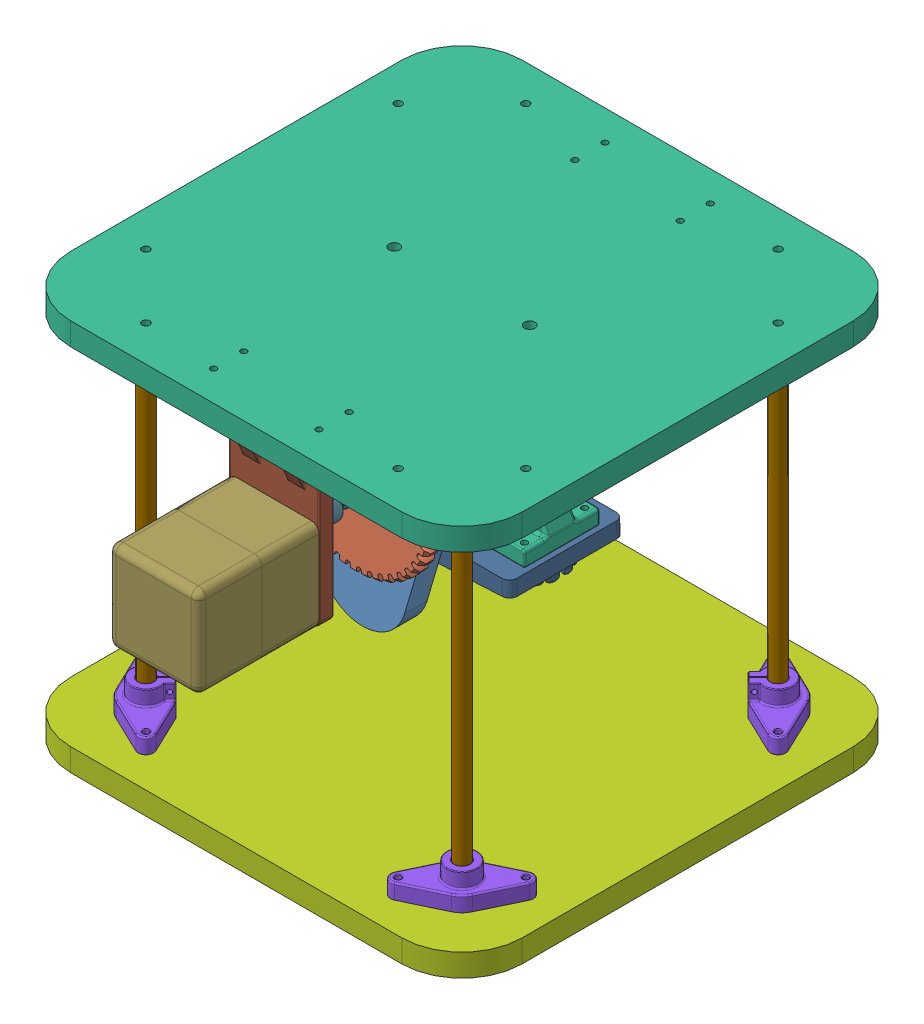
SolidWorks assembly ASSEMBLY Full Design 7th Attempt - New Design For Jaw, configuration Default. Lengths in mm.
Overall size (300 260 410).
35 component instances, 15 part files, 88 mates.
Components (placement in the parent):
- Main Case 02-1: Main Case 02 [Default] x (0.994892 -0.100948 0) z (0 0 1) size (80 129 15)
- Secondary Big Spur Gear-1: Secondary Big Spur Gear [Default] at (0 0 66) x (0.839597 -0.54321 0) z (0 0 1) size (100.6 100.6 10)
- Main Bearing-1: Main Bearing [Default] at (0 0 52.5) x (0.766521 -0.642219 0) z (0 0 1) size (25 25 10)
- Secondary Big Spur Gear-2: Secondary Big Spur Gear [Default] at (0 0 -66) x (-0.772467 -0.635055 0) z (0 0 1) size (100.6 100.6 10)
- Main Bearing-3: Main Bearing [Default] at (0 0 -55) x (0.693553 -0.720406 0) z (0 0 1) size (25 25 10)
- Main Rod-1: Main Rod [Default] at origin size (10 10 70)
- Rod Cap-1: Rod Cap [Default] at (0 0 -35) x (-0.994892 0.100948 0) z (0 0 1) size (44.95 22.5 20)
- Rod Cap-2: Rod Cap [Default] at (0 0 35) x (-0.994892 0.100948 0) z (0 0 1) size (44.95 22.5 20)
- Top Bracket-1: Top Bracket [Default] at (0 72.5 0) size (300 116.9 300)
- Main Bearing-5: Main Bearing [Default] at (0 0 18) size (25 25 10)
- Main Bearing-6: Main Bearing [Default] at (0 0 -18) size (25 25 10)
- Bottom Bracket-1: Bottom Bracket [Default] at (0 -180 0) size (300 15 300)
- Plate Docker-1: Plate Docker [Default] at (105 -165 -105) x (0.707107 0 0.707107) z (-0.707107 0 0.707107) size (70 20.03 29.14)
- Plate Docker-2: Plate Docker [Default] at (105 65 105) x (0.707107 0 -0.707107) z (-0.707107 0 -0.707107) size (70 20.03 29.14)
- Plate Docker-3: Plate Docker [Default] at (-105 65 -105) x (-0.707107 0 0.707107) z (0.707107 0 0.707107) size (70 20.03 29.14)
- Plate Docker-4: Plate Docker [Default] at (-105 -165 105) x (-0.707107 0 -0.707107) z (0.707107 0 -0.707107) size (70 20.03 29.14)
- Plate Docker-5: Plate Docker [Default] at (-105 -165 -105) x (0.707107 0 -0.707107) z (0.707107 0 0.707107) size (70 20.03 29.14)
- Plate Docker-6: Plate Docker [Default] at (-105 65 105) x (0.707107 0 0.707107) z (0.707107 0 -0.707107) size (70 20.03 29.14)
- Plate Docker-7: Plate Docker [Default] at (105 65 -105) x (-0.707107 0 -0.707107) z (-0.707107 0 0.707107) size (70 20.03 29.14)
- Plate Docker-8: Plate Docker [Default] at (105 -165 105) x (-0.707107 0 0.707107) z (-0.707107 0 -0.707107) size (70 20.03 29.14)
- Bracket Shaft-1: Bracket Shaft [Default] at (-105 -165 105) size (10 230 10)
- Bracket Shaft-2: Bracket Shaft [Default] at (-105 -165 -105) size (10 230 10)
- Bracket Shaft-3: Bracket Shaft [Default] at (105 -165 105) size (10 230 10)
- Bracket Shaft-4: Bracket Shaft [Default] at (105 -165 -105) size (10 230 10)
- Ham tren V1-2: Ham tren V1 [Default] at (38.2293 -54.5924 0.5024) x (0 0 -1) z (-0.121869 -0.992546 0) size (76.11 57.29 25.91)
- Motor Mount Plate-1: Motor Mount Plate [Default] at (0 12.5 115) size (80 105 30)
- Motor Mount Plate-2: Motor Mount Plate [Default] at (0 12.5 -125) size (80 105 30)
- Motor-1: Motor [Default] at (-30.0013 -39.9987 163) size (60 60 99)
- Motor-2: Motor [Default] at (30.0013 -39.9987 -163) x (-1 0 0) z (0 0 -1) size (60 60 99)
- Big Motor Shaft-1: Big Motor Shaft [Default] at (0 0 -100) x (0.73445 0.678663 0) z (0.678663 -0.73445 0) size (10 50 10)
- Big Motor Shaft-2: Big Motor Shaft [Default] at (0 0 50) x (0.969145 0.246493 0) z (0.246493 -0.969145 0) size (10 50 10)
- Motor Coupling-1: Motor Coupling [Default] at (0.0013 0.0013 -100.5) x (-1 0 0) z (0 0 -1) size (20 20 25)
- Motor Coupling-2: Motor Coupling [Default] at (-0.0013 0.0013 100.5) size (20 20 25)
- Shaft Lock-3: Shaft Lock [Default] at (0 0 71) x (1 0 0) z (0 -1 0) size (20 10 20)
- Shaft Lock-4: Shaft Lock [Default] at (0 0 -71) x (-1 0 0) z (0 -1 0) size (20 10 20)
Mates (geometry in assembly coordinates):
- Coincident1: coincident aligned: plane of Main Case 02-1 through (0 0 0) normal (0 0 1)
- Concentric2: concentric aligned: cylinder of Main Case 02-1 through (0 0 45) axis (0 0 1) radius 12.5; cylinder of Secondary Big Spur Gear-1 through (0 0 61) axis (0 0 1) radius 5
- Distance1: distance = 1 mm anti-aligned: plane of Secondary Big Spur Gear-1 through (0 0 61) normal (0 0 -1); plane of Main Case 02-1 through (0 0 60) normal (0 0 1)
- Concentric3: concentric anti-aligned: cylinder of Main Case 02-1 through (0 0 45) axis (0 0 1) radius 12.5; cylinder of Main Bearing-1 through (0 0 57.5) axis (0 0 -1) radius 12.5
- Width1: width aligned: plane of Main Bearing-1 through (0 0 47.5) normal (0 0 -1); plane of Main Bearing-1 through (0 0 57.5) normal (0 0 1); plane of Main Case 02-1 through (0 0 45) normal (0 0 -1); plane of Main Case 02-1 through (0 0 60) normal (0 0 1)
- Concentric11: concentric: cylinder of Main Case 02-1 through (0 0 -45) axis (0 0 -1) radius 12.5; cylinder of Secondary Big Spur Gear-2 through (0 0 -71) axis (0 0 1) radius 5
- Distance4: distance = 1 mm: plane of Secondary Big Spur Gear-2 through (0 0 -61) normal (0 0 1); plane of Main Case 02-1 through (0 0 -60) normal (0 0 -1)
- Concentric15: concentric: cylinder of Main Case 02-1 through (0 0 -45) axis (0 0 -1) radius 12.5; cylinder of Main Bearing-3 through (0 0 -50) axis (0 0 -1) radius 5
- Coincident19: coincident: point of Main Case 02-1; point of assembly
- Coincident20: coincident: plane of Main Case 02-1 through (0 0 -60) normal (0 0 -1); plane of Main Bearing-3 through (0 0 -60) normal (0 0 -1)
- Concentric20: concentric: cylinder of Main Case 02-1 through (0 0 35) axis (0 0 -1) radius 5; cylinder of Main Rod-1 through (0 0 35) axis (0 0 -1) radius 5
- Coincident21: coincident: plane of Main Case 02-1 through (0 0 -35) normal (0 0 1); plane of Main Rod-1 through (0 0 -35) normal (0 0 -1)
- Coincident22: coincident: plane of Main Case 02-1 through (-22.3851 2.2713 -25) normal (0.100948 0.994892 0); plane of Rod Cap-1 through (22.3851 -2.2713 -25) normal (-0.100948 -0.994892 0)
- Concentric21: concentric: cylinder of Main Case 02-1 through (11.6608 -21.2859 -35) axis (0.100948 0.994892 0) radius 2; cylinder of Rod Cap-1 through (15.9511 20.997 -35) axis (-0.100948 -0.994892 0) radius 2
- Concentric22: concentric: cylinder of Main Case 02-1 through (-15.6987 -18.5098 -35) axis (0.100948 0.994892 0) radius 2; cylinder of Rod Cap-1 through (-11.4084 23.7731 -35) axis (-0.100948 -0.994892 0) radius 2
- Concentric23: concentric: cylinder of Main Case 02-1 through (11.6608 -21.2859 35) axis (0.100948 0.994892 0) radius 2; cylinder of Rod Cap-2 through (15.9511 20.997 35) axis (-0.100948 -0.994892 0) radius 2
- Coincident23: coincident: plane of Main Case 02-1 through (-22.3851 2.2713 25) normal (0.100948 0.994892 0); plane of Rod Cap-2 through (22.3851 -2.2713 45) normal (-0.100948 -0.994892 0)
- Concentric24: concentric: cylinder of Main Case 02-1 through (-15.6987 -18.5098 35) axis (0.100948 0.994892 0) radius 2; cylinder of Rod Cap-2 through (-11.4084 23.7731 35) axis (-0.100948 -0.994892 0) radius 2
- Concentric26: concentric anti-aligned: cylinder of Main Rod-1 through (0 0 35) axis (0 0 -1) radius 5; cylinder of Top Bracket-1 through (0 0 13) axis (0 0 1) radius 10
- Width4: width: plane of Main Case 02-1 through (0 0 -45) normal (0 0 1); plane of Top Bracket-1 through (0 0 45) normal (0 0 -1); plane of Main Case 02-1 through (0 0 -23) normal (0 0 -1); plane of Top Bracket-1 through (0 0 23) normal (0 0 1)
- Parallel9: parallel anti-aligned: plane of Top Bracket-1 through (-150 65 150) normal (0 -1 0)
- Coincident33: coincident aligned: plane of Top Bracket-1 through (0 0 -23) normal (0 0 -1); plane of Main Bearing-6 through (0 0 -23) normal (0 0 -1)
- Concentric28: concentric aligned: cylinder of Main Rod-1 through (0 0 35) axis (0 0 -1) radius 5; cylinder of Main Bearing-6 through (0 0 -13) axis (0 0 -1) radius 5
- Coincident34: coincident aligned: plane of Top Bracket-1 through (0 0 23) normal (0 0 1); plane of Main Bearing-5 through (0 0 23) normal (0 0 1)
- Concentric29: concentric aligned: cylinder of Main Rod-1 through (0 0 35) axis (0 0 -1) radius 5; cylinder of Main Bearing-5 through (0 0 23) axis (0 0 -1) radius 5
- Coincident35: coincident aligned: plane of Top Bracket-1 through (0 72.5 0) normal (0 0 1); plane of Bottom Bracket-1 through (0 -180 0) normal (0 0 1)
- Coincident36: coincident aligned: plane of Top Bracket-1 through (0 72.5 0) normal (1 0 0); plane of Bottom Bracket-1 through (0 -180 0) normal (1 0 0)
- Distance6: distance = 230 mm anti-aligned: plane of Bottom Bracket-1 through (0 -165 0) normal (0 1 0); plane of Top Bracket-1 through (-150 65 150) normal (0 -1 0)
- Concentric30: concentric anti-aligned: circle of Bottom Bracket-1; cylinder of Plate Docker-1 through (105 -155 -105) axis (0 -1 0) radius 5
- Coincident37: coincident anti-aligned: plane of Bottom Bracket-1 through (0 -165 0) normal (0 1 0); plane of Plate Docker-1 through (83.7868 -165 -126.2132) normal (0 -1 0)
- Concentric31: concentric aligned: cylinder of Bottom Bracket-1 through (126.2132 -180 -83.7868) axis (0 1 0) radius 2.5; cylinder of Plate Docker-1 through (126.2132 -165 -83.7868) axis (0 1 0) radius 2
- Concentric32: concentric aligned: cylinder of Bottom Bracket-1 through (-126.2132 -180 -83.7868) axis (0 1 0) radius 2.5; cylinder of Plate Docker-5 through (-126.2132 -165 -83.7868) axis (0 1 0) radius 2
- Coincident38: coincident anti-aligned: plane of Bottom Bracket-1 through (0 -165 0) normal (0 1 0); plane of Plate Docker-5 through (-126.2132 -165 -83.7868) normal (0 -1 0)
- Concentric33: concentric aligned: cylinder of Bottom Bracket-1 through (-83.7868 -180 -126.2132) axis (0 1 0) radius 2.5; cylinder of Plate Docker-5 through (-83.7868 -165 -126.2132) axis (0 1 0) radius 2
- Coincident39: coincident anti-aligned: plane of Bottom Bracket-1 through (0 -165 0) normal (0 1 0); plane of Plate Docker-8 through (126.2132 -165 83.7868) normal (0 -1 0)
- Concentric35: concentric aligned: cylinder of Bottom Bracket-1 through (83.7868 -180 126.2132) axis (0 1 0) radius 2.5; cylinder of Plate Docker-8 through (83.7868 -165 126.2132) axis (0 1 0) radius 2
- Concentric36: concentric aligned: cylinder of Bottom Bracket-1 through (126.2132 -180 83.7868) axis (0 1 0) radius 2.5; cylinder of Plate Docker-8 through (126.2132 -165 83.7868) axis (0 1 0) radius 2
- Coincident40: coincident anti-aligned: plane of Bottom Bracket-1 through (0 -165 0) normal (0 1 0); plane of Plate Docker-4 through (-83.7868 -165 126.2132) normal (0 -1 0)
- Concentric37: concentric aligned: cylinder of Bottom Bracket-1 through (-126.2132 -180 83.7868) axis (0 1 0) radius 2.5; cylinder of Plate Docker-4 through (-126.2132 -165 83.7868) axis (0 1 0) radius 2
- Concentric38: concentric aligned: cylinder of Bottom Bracket-1 through (-83.7868 -180 126.2132) axis (0 1 0) radius 2.5; cylinder of Plate Docker-4 through (-83.7868 -165 126.2132) axis (0 1 0) radius 2
- Coincident42: coincident anti-aligned: plane of Top Bracket-1 through (-150 65 150) normal (0 -1 0); plane of Plate Docker-2 through (83.7868 65 126.2132) normal (0 1 0)
- Concentric40: concentric aligned: cylinder of Top Bracket-1 through (83.7868 80 126.2132) axis (0 -1 0) radius 2.5; cylinder of Plate Docker-2 through (83.7868 65 126.2132) axis (0 -1 0) radius 2
- Concentric41: concentric aligned: cylinder of Top Bracket-1 through (126.2132 80 83.7868) axis (0 -1 0) radius 2.5; cylinder of Plate Docker-2 through (126.2132 65 83.7868) axis (0 -1 0) radius 2
- Coincident43: coincident anti-aligned: plane of Top Bracket-1 through (-150 65 150) normal (0 -1 0); plane of Plate Docker-6 through (-126.2132 65 83.7868) normal (0 1 0)
- Concentric42: concentric aligned: cylinder of Top Bracket-1 through (-83.7868 80 126.2132) axis (0 -1 0) radius 2.5; cylinder of Plate Docker-6 through (-83.7868 65 126.2132) axis (0 -1 0) radius 2
- Concentric43: concentric aligned: cylinder of Top Bracket-1 through (-126.2132 80 83.7868) axis (0 -1 0) radius 2.5; cylinder of Plate Docker-6 through (-126.2132 65 83.7868) axis (0 -1 0) radius 2
- Coincident44: coincident anti-aligned: plane of Top Bracket-1 through (-150 65 150) normal (0 -1 0); plane of Plate Docker-3 through (-83.7868 65 -126.2132) normal (0 1 0)
- Concentric45: concentric aligned: cylinder of Top Bracket-1 through (-83.7868 80 -126.2132) axis (0 -1 0) radius 2.5; cylinder of Plate Docker-3 through (-83.7868 65 -126.2132) axis (0 -1 0) radius 2
- Concentric46: concentric aligned: cylinder of Top Bracket-1 through (-126.2132 80 -83.7868) axis (0 -1 0) radius 2.5; cylinder of Plate Docker-3 through (-126.2132 65 -83.7868) axis (0 -1 0) radius 2
- Coincident45: coincident anti-aligned: plane of Top Bracket-1 through (-150 65 150) normal (0 -1 0); plane of Plate Docker-7 through (126.2132 65 -83.7868) normal (0 1 0)
- Concentric47: concentric aligned: cylinder of Top Bracket-1 through (83.7868 80 -126.2132) axis (0 -1 0) radius 2.5; cylinder of Plate Docker-7 through (83.7868 65 -126.2132) axis (0 -1 0) radius 2
- Concentric48: concentric aligned: cylinder of Top Bracket-1 through (126.2132 80 -83.7868) axis (0 -1 0) radius 2.5; cylinder of Plate Docker-7 through (126.2132 65 -83.7868) axis (0 -1 0) radius 2
- Concentric49: concentric aligned: cylinder of Plate Docker-4 through (-105 -155 105) axis (0 -1 0) radius 5; cylinder of Bracket Shaft-1 through (-105 65 105) axis (0 -1 0) radius 5
- Coincident46: coincident anti-aligned: plane of Top Bracket-1 through (-150 65 150) normal (0 -1 0); plane of Bracket Shaft-1 through (-105 65 105) normal (0 1 0)
- Concentric50: concentric anti-aligned: cylinder of Plate Docker-7 through (105 55 -105) axis (0 1 0) radius 5; cylinder of Bracket Shaft-4 through (105 65 -105) axis (0 -1 0) radius 5
- Coincident47: coincident anti-aligned: plane of Top Bracket-1 through (-150 65 150) normal (0 -1 0); plane of Bracket Shaft-4 through (105 65 -105) normal (0 1 0)
- Concentric51: concentric anti-aligned: cylinder of Plate Docker-2 through (105 45 105) axis (0 1 0) radius 10; cylinder of Bracket Shaft-3 through (105 65 105) axis (0 -1 0) radius 5
- Coincident48: coincident anti-aligned: plane of Top Bracket-1 through (-150 65 150) normal (0 -1 0); plane of Bracket Shaft-3 through (105 65 105) normal (0 1 0)
- Concentric52: concentric aligned: cylinder of Plate Docker-5 through (-105 -155 -105) axis (0 -1 0) radius 5; cylinder of Bracket Shaft-2 through (-105 65 -105) axis (0 -1 0) radius 5
- Coincident49: coincident anti-aligned: plane of Top Bracket-1 through (-150 65 150) normal (0 -1 0); plane of Bracket Shaft-2 through (-105 65 -105) normal (0 1 0)
- Coincident73: coincident anti-aligned: plane of Top Bracket-1 through (16.5 -36.9 25) normal (0 -1 0); plane of Ham tren V1-2 through (38.2293 -36.9 -94.448) normal (0 1 0)
- Concentric59: concentric aligned: cylinder of Top Bracket-1 through (61.5 -46.9 -20) axis (0 1 0) radius 2; cylinder of Ham tren V1-2 through (61.5 -44.9 -20) axis (0 1 0) radius 2
- Concentric60: concentric aligned: cylinder of Top Bracket-1 through (61.5 -46.9 20) axis (0 1 0) radius 2; cylinder of Ham tren V1-2 through (61.5 -44.9 20) axis (0 1 0) radius 2
- Coincident74: coincident anti-aligned: plane of Top Bracket-1 through (-150 65 150) normal (0 -1 0); plane of Motor Mount Plate-1 through (-30 65 125) normal (0 1 0)
- Coincident75: coincident anti-aligned: plane of Top Bracket-1 through (-150 65 150) normal (0 -1 0); plane of Motor Mount Plate-2 through (-30 65 -115) normal (0 1 0)
- Concentric61: concentric anti-aligned: cylinder of Top Bracket-1 through (-35 80 -130) axis (0 -1 0) radius 2; cylinder of Motor Mount Plate-2 through (-35 55 -130) axis (0 1 0) radius 2
- Concentric62: concentric anti-aligned: cylinder of Top Bracket-1 through (35 80 -110) axis (0 -1 0) radius 2; cylinder of Motor Mount Plate-2 through (35 55 -110) axis (0 1 0) radius 2
- Concentric63: concentric anti-aligned: cylinder of Top Bracket-1 through (35 80 130) axis (0 -1 0) radius 2; cylinder of Motor Mount Plate-1 through (35 55 130) axis (0 1 0) radius 2
- Concentric64: concentric anti-aligned: cylinder of Top Bracket-1 through (-35 80 110) axis (0 -1 0) radius 2; cylinder of Motor Mount Plate-1 through (-35 55 110) axis (0 1 0) radius 2
- Coincident76: coincident anti-aligned: plane of Motor Mount Plate-1 through (0 12.5 125) normal (0 0 1); plane of Motor-1 through (-30.0013 -39.9987 125) normal (0 0 -1)
- Tangent1: tangent aligned: cylinder of Motor-1 through (-24.75 14.75 135) axis (0 0 -1) radius 2.25; cylinder of Motor Mount Plate-1 through (-24.75 14.75 105) axis (0 0 1) radius 2.25
- Coincident78: coincident anti-aligned: plane of Motor Mount Plate-2 through (0 12.5 -125) normal (0 0 -1); plane of Motor-2 through (30.0013 -39.9987 -125) normal (0 0 1)
- Concentric71: concentric aligned: cylinder of Motor Mount Plate-2 through (24.75 14.75 -135) axis (0 0 1) radius 2.25; cylinder of Motor-2 through (24.75 14.75 -135) axis (0 0 1) radius 2.25
- Parallel28: parallel aligned: cylinder of Motor Mount Plate-2 through (-24.75 14.75 -135) axis (0 0 1) radius 2.25; cylinder of Motor-2 through (-24.7475 14.75 -135) axis (0 0 1) radius 2.25
- Parallel29: parallel aligned: plane of Motor Mount Plate-1 through (0 12.5 115) normal (1 0 0); plane of Motor-1 through (-30.0013 -39.9987 163) normal (1 0 0)
- Parallel30: parallel anti-aligned: plane of Motor Mount Plate-2 through (0 12.5 -125) normal (1 0 0); plane of Motor-2 through (30.0013 -39.9987 -163) normal (-1 0 0)
- Concentric75: concentric anti-aligned: cylinder of Secondary Big Spur Gear-1 through (0 0 61) axis (0 0 1) radius 5; cylinder of Big Motor Shaft-2 through (0 0 100) axis (0 0 -1) radius 5
- Coincident81: coincident: plane of Main Case 02-1 through (0 0 50) normal (0 0 1); plane of Big Motor Shaft-2 through (0 0 50) normal (0 0 -1)
- Concentric76: concentric anti-aligned: circle of Main Bearing-3; cylinder of Big Motor Shaft-1 through (0 0 -50) axis (0 0 -1) radius 5
- Coincident82: coincident: plane of Main Case 02-1 through (0 0 -50) normal (0 0 -1); plane of Big Motor Shaft-1 through (0 0 -50) normal (0 0 1)
- Distance9: distance = 7 mm anti-aligned: plane of Motor Coupling-1 through (0.0013 0.0013 -113) normal (0 0 -1); plane of Motor-2 through (0.0013 0.0013 -106) normal (0 0 1)
- Concentric77: concentric aligned: cylinder of Motor-2 through (0.0013 0.0013 -106) axis (0 0 -1) radius 2.5; cylinder of Motor Coupling-1 through (0.0013 0.0013 -105) axis (0 0 -1) radius 2.5
- Distance10: distance = 7 mm anti-aligned: plane of Motor Coupling-2 through (-0.0013 0.0013 113) normal (0 0 1); plane of Motor-1 through (-0.0013 0.0013 106) normal (0 0 -1)
- Concentric78: concentric anti-aligned: cylinder of Motor-1 through (-0.0013 0.0013 106) axis (0 0 1) radius 2.5; cylinder of Motor Coupling-2 through (-0.0013 0.0013 113) axis (0 0 -1) radius 10
- Concentric79: concentric aligned: cylinder of Big Motor Shaft-2 through (0 0 100) axis (0 0 -1) radius 5; cylinder of Shaft Lock-3 through (0 0 74) axis (0 0 -1) radius 5
- Coincident85: coincident anti-aligned: plane of Secondary Big Spur Gear-1 through (0 0 71) normal (0 0 1); plane of Shaft Lock-3 through (0 0 71) normal (0 0 -1)
- Concentric80: concentric anti-aligned: cylinder of Big Motor Shaft-1 through (0 0 -50) axis (0 0 -1) radius 5; cylinder of Shaft Lock-4 through (0 0 -74) axis (0 0 1) radius 5
- Coincident86: coincident anti-aligned: plane of Secondary Big Spur Gear-2 through (0 0 -71) normal (0 0 -1); plane of Shaft Lock-4 through (0 0 -71) normal (0 0 1)
